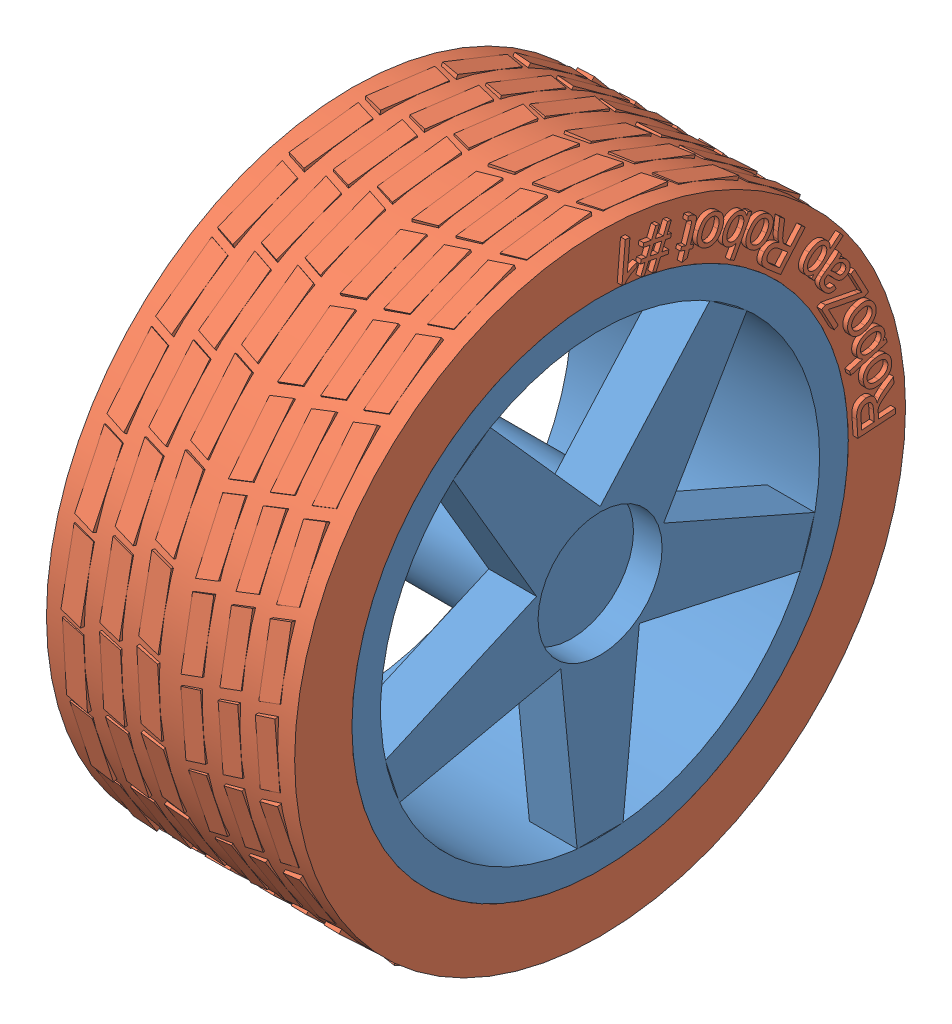
SolidWorks assembly RZ-R1-2001-1, configuration По умолчанию. Lengths in mm.
Overall size (30.5 64.6 64.73).
2 component instances, 2 part files, 2 mates.
Components (placement in the parent):
- RZ-R1-6003-1-1: RZ-R1-6003-1 [По умолчанию] at (29.3347 39.193 46.9322) x (-1 0 0) z (0 0 -1) size (30 52 52)
- RZ-R1-6004-1-1: RZ-R1-6004-1 [По умолчанию] at (3.3347 39.193 46.9322) size (26.5 64.6 64.73)
Mates (geometry in assembly coordinates):
- Концентричный1: concentric anti-aligned: circle of RZ-R1-6003-1-1; circle of RZ-R1-6004-1-1
- Касательность2: tangent: circle of RZ-R1-6003-1-1; circle of RZ-R1-6004-1-1
